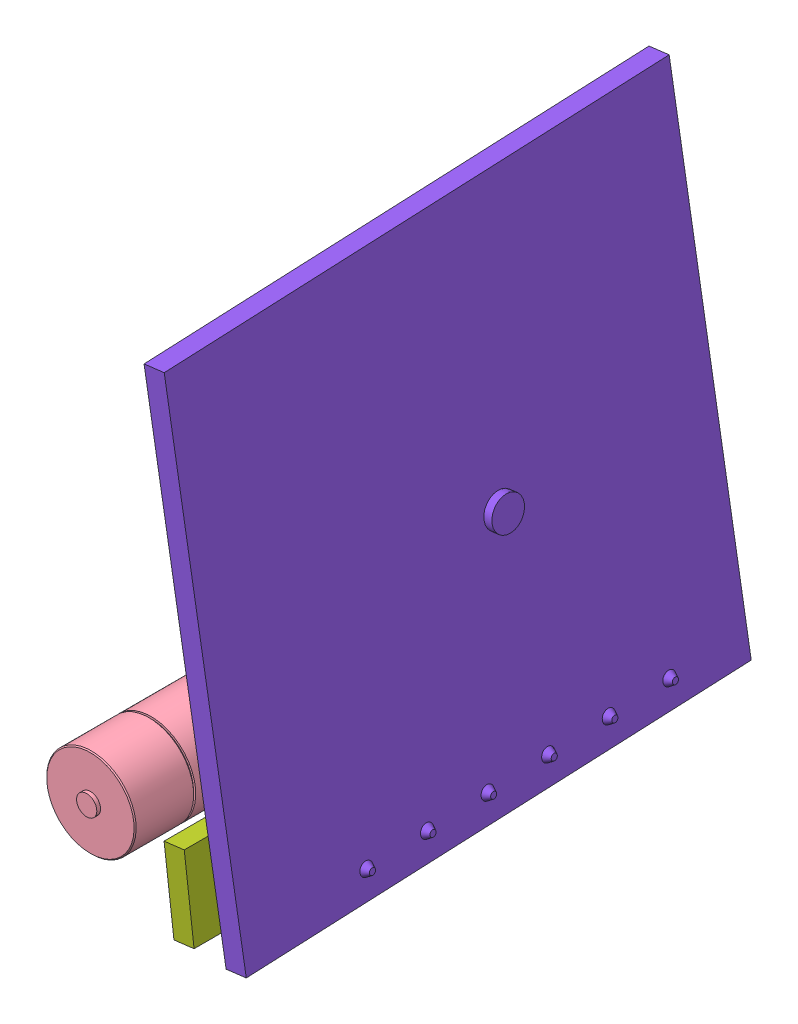
SolidWorks assembly 装配体1, configuration 默认. Lengths in mm.
Overall size (158.05 299.59 263.76).
23 component instances, 8 part files, 7 mates.
Components (placement in the parent):
- 麦轮-1: 麦轮 [默认] at (5.9565 -11.7352 121.239) size (121.74 121.74 23.04)
- 滚轮-1: 滚轮 [默认] at (57.4055 -35.0188 113.8375) x (0.958316 -0.065431 -0.278117) z (0.278117 0.436557 0.85561) size (11.01 11.01 20)
- 滚轮-2: 滚轮 [默认] at (62.3994 -13.5577 113.8375) x (0.910408 0.306281 -0.278117) z (0.089884 0.509757 0.85561) size (11.01 11.01 20)
- 滚轮-3: 滚轮 [默认] at (58.8004 8.1808 113.8375) x (0.723898 0.631365 -0.278117) z (-0.112034 0.505351 0.85561) size (11.01 11.01 20)
- 滚轮-4: 滚轮 [默认] at (47.1564 26.8873 113.8375) x (0.427182 0.860329 -0.278117) z (-0.296895 0.42401 0.85561) size (11.01 11.01 20)
- 滚轮-5: 滚轮 [默认] at (29.2401 39.7138 113.8375) x (0.065431 0.958316 -0.278117) z (-0.436557 0.278117 0.85561) size (11.01 11.01 20)
- 滚轮-6: 滚轮 [默认] at (7.779 44.7077 113.8375) x (-0.306281 0.910408 -0.278117) z (-0.509757 0.089884 0.85561) size (11.01 11.01 20)
- 滚轮-7: 滚轮 [默认] at (-13.9595 41.1087 113.8375) x (-0.631365 0.723898 -0.278117) z (-0.505351 -0.112034 0.85561) size (11.01 11.01 20)
- 滚轮-8: 滚轮 [默认] at (-32.666 29.4647 113.8375) x (-0.860329 0.427182 -0.278117) z (-0.42401 -0.296895 0.85561) size (11.01 11.01 20)
- 滚轮-9: 滚轮 [默认] at (-45.4925 11.5484 113.8375) x (-0.958316 0.065431 -0.278117) z (-0.278117 -0.436557 0.85561) size (11.01 11.01 20)
- 滚轮-10: 滚轮 [默认] at (-50.4864 -9.9127 113.8375) x (-0.910408 -0.306281 -0.278117) z (-0.089884 -0.509757 0.85561) size (11.01 11.01 20)
- 滚轮-11: 滚轮 [默认] at (-46.8874 -31.6512 113.8375) x (-0.723898 -0.631365 -0.278117) z (0.112034 -0.505351 0.85561) size (11.01 11.01 20)
- 滚轮-12: 滚轮 [默认] at (-35.2434 -50.3577 113.8375) x (-0.427182 -0.860329 -0.278117) z (0.296895 -0.42401 0.85561) size (11.01 11.01 20)
- 滚轮-13: 滚轮 [默认] at (-17.3271 -63.1842 113.8375) x (-0.065431 -0.958316 -0.278117) z (0.436557 -0.278117 0.85561) size (11.01 11.01 20)
- 滚轮-14: 滚轮 [默认] at (4.134 -68.1782 113.8375) x (0.306281 -0.910408 -0.278117) z (0.509757 -0.089884 0.85561) size (11.01 11.01 20)
- 滚轮-15: 滚轮 [默认] at (25.8725 -64.5791 113.8375) x (0.631365 -0.723898 -0.278117) z (0.505351 0.112034 0.85561) size (11.01 11.01 20)
- 滚轮-16: 滚轮 [默认] at (44.579 -52.9351 113.8375) x (0.860329 -0.427182 -0.278117) z (0.42401 0.296895 0.85561) size (11.01 11.01 20)
- 电机连接轴SLDPRT-1: 电机连接轴SLDPRT [默认] at (5.9565 -11.7352 133.293) size (56 56 26)
- 电机3D-1: 电机3D [默认] at (5.9565 -11.7352 244.293) x (0.974614 0.22389 0) z (-0.22389 0.974614 0) size (44 85 44)
- 电机连接轴反-2: 电机连接轴反 [默认] at (5.9565 -11.7352 110.3024) x (-0.789199 -0.614137 0) z (0 0 -1) size (56 56 30)
- 支撑板-1: 支撑板 [默认] at (5.9565 -11.7352 84.471) x (-0.057859 0.998325 0) z (0 0 -1) size (44 110.69 40)
- 内侧电机支撑板SLDPRT-1: 内侧电机支撑板SLDPRT [默认] at (5.9565 -11.7352 161.293) x (0.121326 -0.992613 0) z (0 0 1) size (40 95 109)
- 平面板-1: 平面板 [默认] at (77.0113 107.5312 184.1646) x (0.121227 -0.991804 -0.040364) z (-0.992613 -0.121326 0) size (250 250 14)
Mates (geometry in assembly coordinates):
- 重合1: coincident: circle of assembly; circle of assembly; circle of 麦轮-1; circle of 滚轮-1
- 同心1: concentric: circle of assembly; circle of assembly; circle of 麦轮-1; circle of 电机连接轴SLDPRT-1
- 重合2: coincident: circle of assembly; circle of assembly; circle of 电机连接轴SLDPRT-1; circle of 电机3D-1
- 同心4: concentric: circle of assembly; circle of assembly; circle of 麦轮-1; circle of 电机连接轴反-2
- 重合4: coincident: cylinder of assembly; circle of assembly; cylinder of 电机连接轴反-2 through (5.9565 -11.7352 84.3024) axis (0 0 -1) radius 6; circle of 支撑板-1
- 重合5: coincident: circle of assembly; circle of assembly; circle of 电机3D-1; circle of 内侧电机支撑板SLDPRT-1
- 重合6: coincident: plane of assembly; plane of assembly; plane of 内侧电机支撑板SLDPRT-1 through (80.4025 -2.6358 161.293) normal (0.992613 0.121326 0); plane of 平面板-1 through (67.0852 106.3179 184.1646) normal (-0.992613 -0.121326 0)
